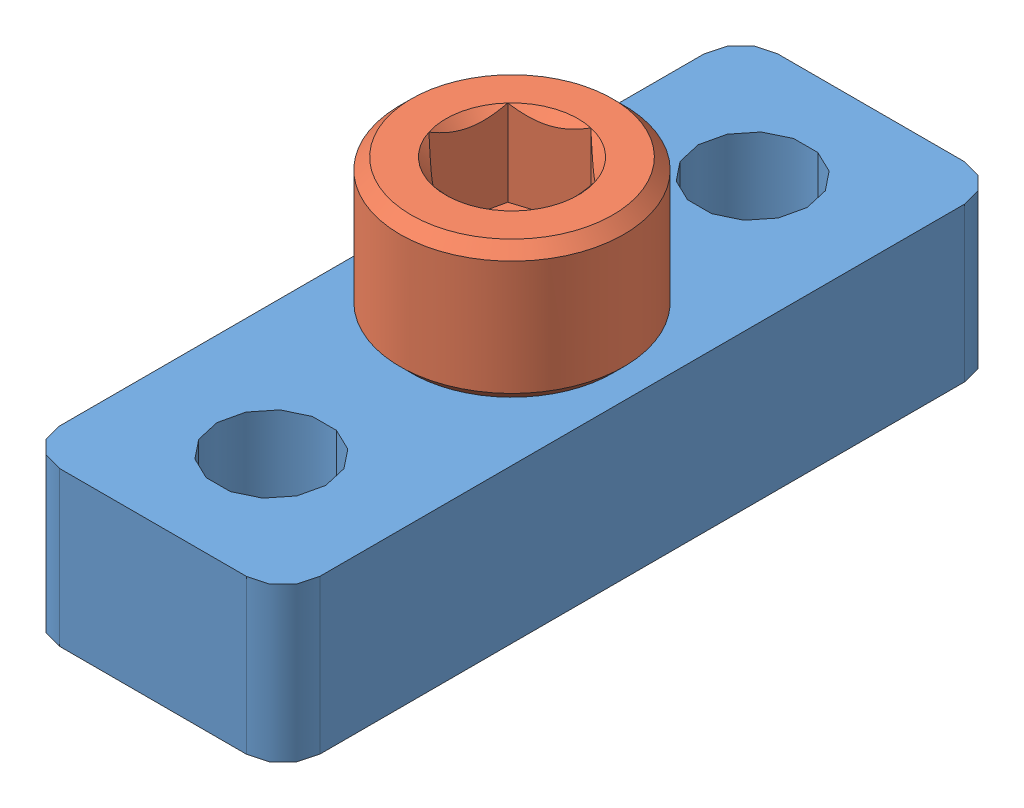
SolidWorks assembly Drive Lug_x, configuration Default. Lengths in mm.
Overall size (5.84 6.24 14.92).
2 component instances, 2 part files, 2 mates.
Components (placement in the parent):
- Drive Lug_x-1: Drive Lug_x [Default] at origin size (5.41 3.2 14.92)
- 97334A104_NYLON SOCKET HEAD CAP SCREW-1: 97334A104_NYLON SOCKET HEAD CAP SCREW [97334A104] at (2.7045 0.0254 0) x (0.302379 0 0.953188) z (0 -1 0) size (4.65 4.65 6.24)
Mates (geometry in assembly coordinates):
- Concentric1: concentric: cylinder of Drive Lug_x-1 through (2.7045 6.3974 0) axis (0 -1 0) radius 1.1303; cylinder of 97334A104_NYLON SOCKET HEAD CAP SCREW-1 through (2.7045 6.0452 0) axis (0 -1 0) radius 2.3241
- Coincident1: coincident: plane of Drive Lug_x-1 through (0 3.2004 7.46) normal (0 1 0); plane of 97334A104_NYLON SOCKET HEAD CAP SCREW-1 through (2.7045 3.2004 0) normal (0 -1 0)
